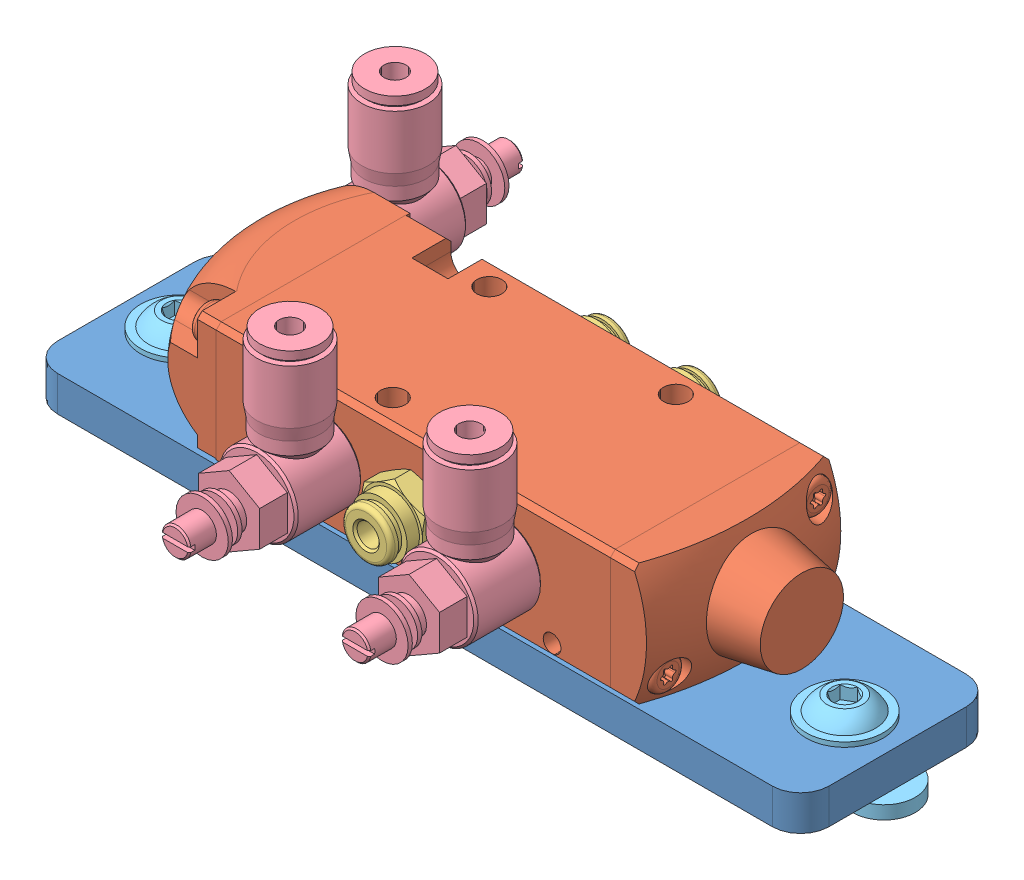
SolidWorks assembly ControlSubAssembly, configuration Default. Lengths in mm.
Overall size (145.26 49.82 88.3).
10 component instances, 5 part files, 18 mates.
Components (placement in the parent):
- DirectionalValveMountingPlate-1: DirectionalValveMountingPlate [Default] at (64.2328 50.534 99.7528) size (138.91 6.35 34.92)
- 6124K404_AIR DIRECTIONAL CONTROL VALVE-1: 6124K404_AIR DIRECTIONAL CONTROL VALVE [Default] at (64.2688 67.884 112.7528) x (0 1 0) z (-1 0 0) size (22.43 40.41 109.13)
- 5225K711_PUSH-TO-CONNECT TUBE FITTING FOR AIR (1)-1: 5225K711_PUSH-TO-CONNECT TUBE FITTING FOR AIR (1) [5225K711] at (64.2688 67.884 123.5498) x (-1 0 0) z (0 0 -1) size (11 12.7 15.49)
- 45045K36_AIR FLOW CONTROL VALVE-1: 45045K36_AIR FLOW CONTROL VALVE [Default] at (48.0688 67.8841 136.2528) x (0 1 0) z (1 0 0) size (30.5 35.17 14.2)
- 45045K36_AIR FLOW CONTROL VALVE-2: 45045K36_AIR FLOW CONTROL VALVE [Default] at (80.4688 67.8839 136.2528) x (0 1 0) z (1 0 0) size (30.5 35.17 14.2)
- 5225K711_PUSH-TO-CONNECT TUBE FITTING FOR AIR (1)-2: 5225K711_PUSH-TO-CONNECT TUBE FITTING FOR AIR (1) [5225K711] at (72.3688 67.884 101.9559) size (11 12.7 15.49)
- 5225K711_PUSH-TO-CONNECT TUBE FITTING FOR AIR (1)-3: 5225K711_PUSH-TO-CONNECT TUBE FITTING FOR AIR (1) [5225K711] at (56.1688 67.884 101.9559) size (11 12.7 15.49)
- 45045K36_AIR FLOW CONTROL VALVE-4: 45045K36_AIR FLOW CONTROL VALVE [Default] at (20.0688 70.184 89.3528) x (0 1 0) z (-1 0 0) size (30.5 35.17 14.2)
- 47065T142_ALUMINUM T-SLOTTED FRAMING EXTRUSION-1: 47065T142_ALUMINUM T-SLOTTED FRAMING EXTRUSION [47065T142] at (4.5732 56.884 112.7068) size (25.4 16.7 13.87)
- 47065T142_ALUMINUM T-SLOTTED FRAMING EXTRUSION-2: 47065T142_ALUMINUM T-SLOTTED FRAMING EXTRUSION [47065T142] at (124.4308 56.884 112.7068) size (25.4 16.7 13.87)
Mates (geometry in assembly coordinates):
- Coincident1: coincident: line of DirectionalValveMountingPlate-1 through (47.4688 56.884 99.7528) axis (0 -1 0); line of 6124K404_AIR DIRECTIONAL CONTROL VALVE-1 through (47.4688 56.884 99.7528) axis (0 1 0)
- Coincident2: coincident anti-aligned: plane of DirectionalValveMountingPlate-1 through (64.2328 56.884 99.7528) normal (0 1 0); plane of 6124K404_AIR DIRECTIONAL CONTROL VALVE-1 through (116.7688 56.884 130.2528) normal (0 -1 0)
- Coincident3: coincident: line of 6124K404_AIR DIRECTIONAL CONTROL VALVE-1 through (64.2688 67.884 130.2528) axis (0 0 -1); line of 5225K711_PUSH-TO-CONNECT TUBE FITTING FOR AIR (1)-1 through (64.2688 67.884 124.5128) axis (0 0 -1)
- Coincident4: coincident anti-aligned: plane of 6124K404_AIR DIRECTIONAL CONTROL VALVE-1 through (116.7688 56.884 130.2528) normal (0 0 1); plane of 5225K711_PUSH-TO-CONNECT TUBE FITTING FOR AIR (1)-1 through (58.7688 77.4102 130.2528) normal (0 0 -1)
- Coincident5: coincident anti-aligned: plane of 6124K404_AIR DIRECTIONAL CONTROL VALVE-1 through (116.7688 56.884 130.2528) normal (0 0 1); plane of 45045K36_AIR FLOW CONTROL VALVE-1 through (48.0688 61.1841 130.2528) normal (0 0 -1)
- Coincident6: coincident: line of 6124K404_AIR DIRECTIONAL CONTROL VALVE-1 through (48.0688 67.8841 130.2528) axis (0 0 -1); line of 45045K36_AIR FLOW CONTROL VALVE-1 through (48.0688 67.8841 122.0532) axis (0 0 1)
- Coincident7: coincident: line of 6124K404_AIR DIRECTIONAL CONTROL VALVE-1 through (80.4688 67.8839 130.2528) axis (0 0 -1); line of 45045K36_AIR FLOW CONTROL VALVE-2 through (80.4688 67.8839 122.0532) axis (0 0 1)
- Coincident8: coincident anti-aligned: plane of 6124K404_AIR DIRECTIONAL CONTROL VALVE-1 through (116.7688 56.884 130.2528) normal (0 0 1); plane of 45045K36_AIR FLOW CONTROL VALVE-2 through (80.4688 61.1839 130.2528) normal (0 0 -1)
- Coincident9: coincident: line of 6124K404_AIR DIRECTIONAL CONTROL VALVE-1 through (72.3688 67.884 95.2528) axis (0 0 1); line of 5225K711_PUSH-TO-CONNECT TUBE FITTING FOR AIR (1)-2 through (72.3688 67.884 100.9929) axis (0 0 1)
- Coincident10: coincident anti-aligned: plane of 6124K404_AIR DIRECTIONAL CONTROL VALVE-1 through (116.7688 56.884 95.2528) normal (0 0 -1); plane of 5225K711_PUSH-TO-CONNECT TUBE FITTING FOR AIR (1)-2 through (77.8688 77.4102 95.2528) normal (0 0 1)
- Coincident11: coincident: line of 6124K404_AIR DIRECTIONAL CONTROL VALVE-1 through (56.1688 67.884 95.2528) axis (0 0 1); line of 5225K711_PUSH-TO-CONNECT TUBE FITTING FOR AIR (1)-3 through (56.1688 67.884 100.9929) axis (0 0 1)
- Coincident12: coincident anti-aligned: plane of 6124K404_AIR DIRECTIONAL CONTROL VALVE-1 through (116.7688 56.884 95.2528) normal (0 0 -1); plane of 5225K711_PUSH-TO-CONNECT TUBE FITTING FOR AIR (1)-3 through (61.6688 77.4102 95.2528) normal (0 0 1)
- Coincident14: coincident: line of 6124K404_AIR DIRECTIONAL CONTROL VALVE-1 through (20.0688 70.184 95.1673) axis (0 0 1); line of 45045K36_AIR FLOW CONTROL VALVE-4 through (20.0688 70.184 103.5525) axis (0 0 -1)
- Coincident15: coincident anti-aligned: plane of 6124K404_AIR DIRECTIONAL CONTROL VALVE-1 through (22.2484 69.384 95.3528) normal (0 0 -1); plane of 45045K36_AIR FLOW CONTROL VALVE-4 through (20.0688 63.484 95.3528) normal (0 0 1)
- Coincident16: coincident aligned: line of DirectionalValveMountingPlate-1 through (4.5732 56.884 112.7068) axis (0 -1 0); line of 47065T142_ALUMINUM T-SLOTTED FRAMING EXTRUSION-1 through (4.5732 57.7222 112.7068) axis (0 -1 0)
- Coincident17: coincident anti-aligned: plane of DirectionalValveMountingPlate-1 through (64.2328 56.884 99.7528) normal (0 1 0); plane of 47065T142_ALUMINUM T-SLOTTED FRAMING EXTRUSION-1 through (11.5074 56.884 112.7068) normal (0 -1 0)
- Coincident18: coincident aligned: line of DirectionalValveMountingPlate-1 through (124.4308 56.884 112.7068) axis (0 -1 0); line of 47065T142_ALUMINUM T-SLOTTED FRAMING EXTRUSION-2 through (124.4308 57.7222 112.7068) axis (0 -1 0)
- Coincident19: coincident anti-aligned: plane of DirectionalValveMountingPlate-1 through (64.2328 56.884 99.7528) normal (0 1 0); plane of 47065T142_ALUMINUM T-SLOTTED FRAMING EXTRUSION-2 through (131.365 56.884 112.7068) normal (0 -1 0)
